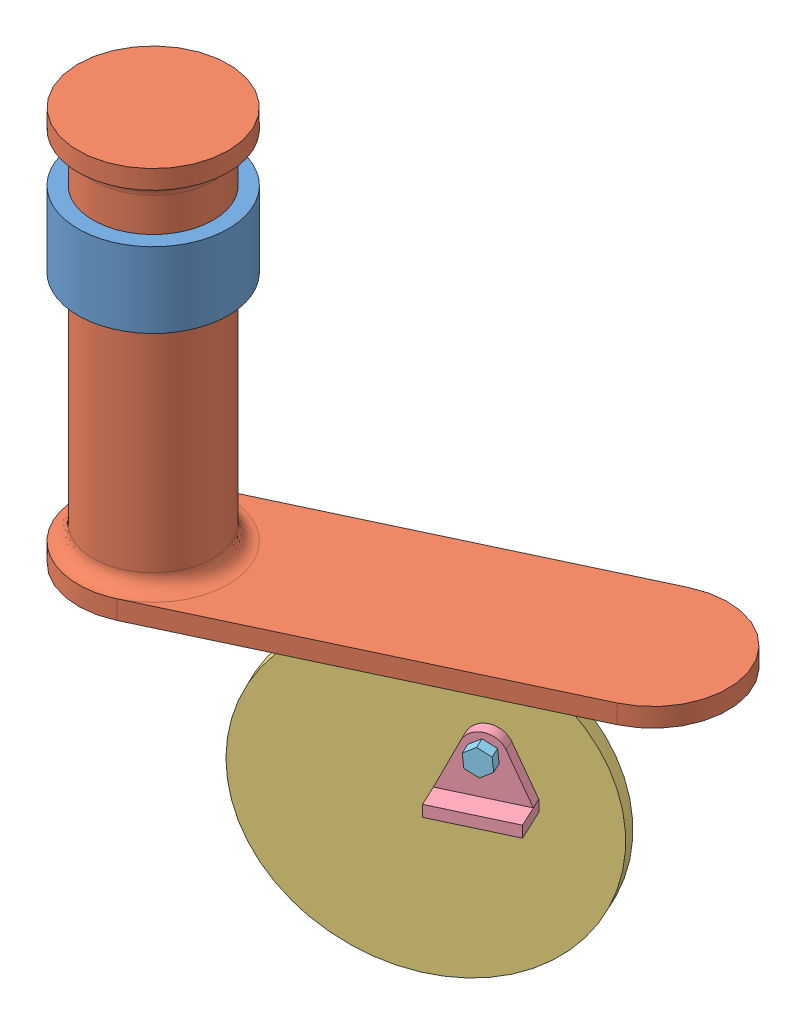
SolidWorks assembly 凸轮机构, configuration 默认. Lengths in mm.
Overall size (143.73 201.27 95.7).
6 component instances, 6 part files, 9 mates.
Components (placement in the parent):
- 轴承1-1: 轴承1 [默认] at (-4.5877 23.0219 0.2788) x (0.978714 0 0.205231) z (-0.205231 0 0.978714) size (40 20 40)
- 活塞-1: 活塞 [默认] at (-4.5877 0.8501 0.2788) x (0.905224 0 -0.424934) z (0.424934 0 0.905224) size (140 105 40)
- 圆盘-1: 圆盘 [默认] at (45.4606 -83.9652 -23.2151) x (-0.570624 -0.776297 0.267864) z (0.424934 0 0.905224) size (80 80 4)
- 支座4-1: 支座4 [默认] at (57.723 -68.4393 -26.7619) x (0.905224 0 -0.424934) z (0.424934 0 0.905224) size (20 18 9)
- 螺钉4,12-1: 螺钉4,12 [默认] at (58.9978 -68.4393 -24.0463) x (0.905224 0 -0.424934) z (0.424934 0 0.905224) size (6.28 6.9 15)
- 螺母4-1: 螺母4 [默认] at (56.0232 -68.4393 -30.3828) x (-0.788301 -0.491575 0.370047) z (-0.424934 0 -0.905224) size (6.9 6.3 3)
Mates (geometry in assembly coordinates):
- 同心1: concentric anti-aligned: cylinder of 轴承1-1 through (-4.5877 43.0219 0.2788) axis (0 -1 0) radius 16; cylinder of 活塞-1 through (-4.5877 61.0348 0.2788) axis (0 1 0) radius 16
- 重合1: coincident aligned: plane of 活塞-1 through (-4.5877 0.8501 0.2788) normal (0.424934 0 0.905224); plane of 圆盘-1 through (45.4606 -83.9652 -23.2151) normal (0.424934 0 0.905224)
- 重合2: coincident anti-aligned: plane of 圆盘-1 through (46.3105 -83.9652 -21.4047) normal (0.424934 0 0.905224); plane of 支座4-1 through (57.723 -68.4393 -26.7619) normal (-0.424934 0 -0.905224)
- 同心2: concentric anti-aligned: cylinder of 支座4-1 through (58.9978 -68.4393 -24.0463) axis (-0.424934 0 -0.905224) radius 2; cylinder of 螺钉4,12-1 through (53.8986 -68.4393 -34.909) axis (0.424934 0 0.905224) radius 2
- 重合3: coincident anti-aligned: plane of 支座4-1 through (58.9978 -68.4393 -24.0463) normal (0.424934 0 0.905224); plane of 螺钉4,12-1 through (59.2686 -71.8904 -24.1734) normal (-0.424934 0 -0.905224)
- 同心3: concentric anti-aligned: cylinder of 圆盘-1 through (57.723 -68.4393 -26.7619) axis (-0.424934 0 -0.905224) radius 2; cylinder of 螺钉4,12-1 through (53.8986 -68.4393 -34.909) axis (0.424934 0 0.905224) radius 2
- 同心4: concentric aligned: cylinder of 螺钉4,12-1 through (53.8986 -68.4393 -34.909) axis (0.424934 0 0.905224) radius 2; cylinder of 螺母4-1 through (54.7484 -68.4393 -33.0985) axis (0.424934 0 0.905224) radius 2
- 重合5: coincident anti-aligned: plane of 圆盘-1 through (44.6108 -83.9652 -25.0256) normal (-0.424934 0 -0.905224); plane of 螺母4-1 through (56.2923 -71.8906 -30.5092) normal (0.424934 0 0.905224)
- 相切2: tangent: plane of 活塞-1 through (-4.5877 -12.9134 0.2788) normal (0 -1 0); cylinder of 圆盘-1 through (69.1355 -52.9134 -32.1192) axis (-0.424934 0 -0.905224) radius 40
